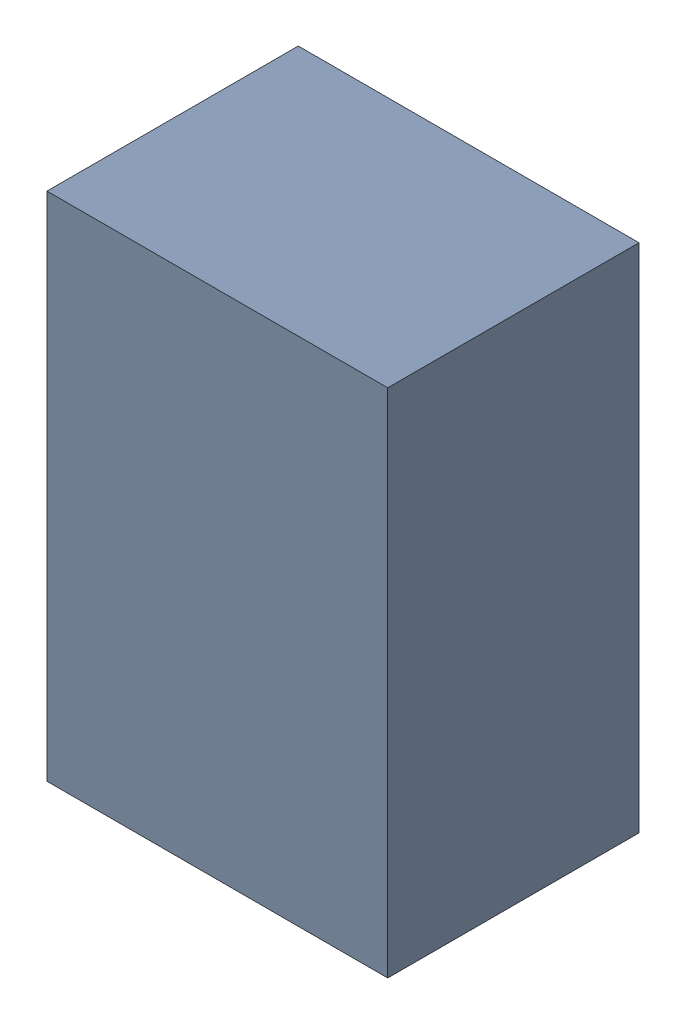
SolidWorks assembly D201, configuration Standard. Lengths in mm.
Overall size (0.8 1.2 0.59).
2 component instances, 1 part files, 0 mates.
Components (placement in the parent):
- 885541832-1: 885541832 [Standard] at (6 -20.4968 0) size (0.8 1.2 0.59)
  - Extruded_31-1: Extruded_31 [Standard] at origin size (0.8 1.2 0.59)
